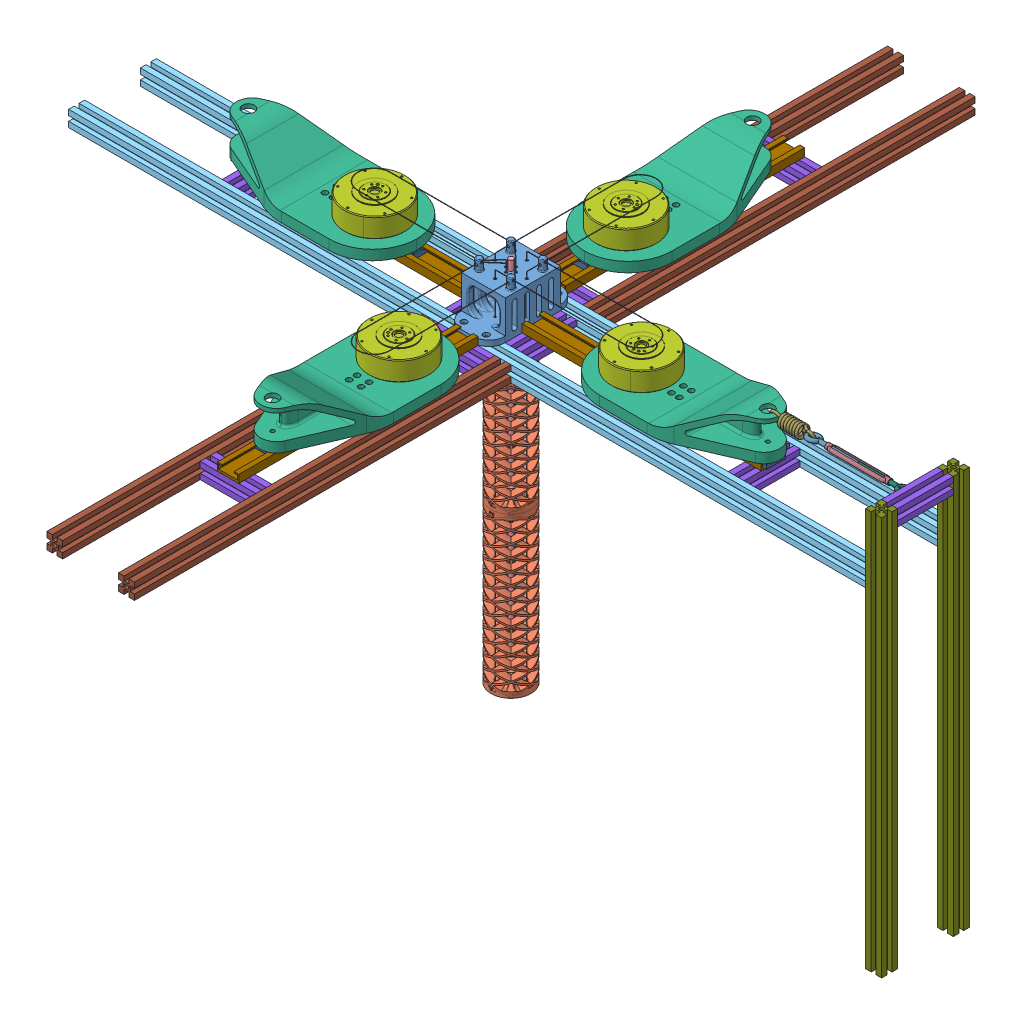
SolidWorks assembly Assemblage, configuration Default. Lengths in mm.
Overall size (1020 500 1055).
53 component instances, 20 part files, 137 mates.
Components (placement in the parent):
- Base-1: Base [Défaut] at (31.9526 22.2291 35.5804) size (55 61.5 110)
- Pièce1-1: Pièce1 [Défaut] at (31.9526 -119.2709 35.5804) x (-1 0 0) z (0 0 1) size (50.03 200 50.02)
- rondelle accroche-1: rondelle accroche [Défaut] at (31.9526 -219.2709 35.5804) size (45.5 4 45.5)
- Pièce1-2: Pièce1 [Défaut] at (31.9526 -319.2709 35.5804) x (-1 0 0) z (0 0 1) size (50.03 200 50.02)
- rondelle accroche-2: rondelle accroche [Défaut] at (31.9526 -419.2709 35.5804) size (45.5 4 45.5)
- Âme-1: Âme [Défaut] at (31.9526 -388.7709 35.5804) size (6 430 6)
- profilé-1: profilé [Défaut] at (-468.0474 -29.2709 80.5804) size (1000 20 20)
- profilé-2: profilé [Défaut] at (-468.0474 -29.2709 -9.4196) size (1000 20 20)
- Support Moteur-1: Support Moteur [Défaut] at (-191.4565 -9.2709 -19.4196) x (0 0 1) z (-1 0 0) size (110 48.5 226.09)
- RMD-X6-V2-1: RMD-X6-V2 [Défaut] at (-460.2739 760.2284 221.0931) x (0 -1 0) z (0.5 0 0.866025) size (38.5 76 76)
- profilé70-1: profilé70 [Défaut] at (-5.5474 -29.2709 70.5804) x (0 0 -1) z (1 0 0) size (70 20 20)
- profilé70-2: profilé70 [Défaut] at (69.4526 -29.2709 70.5804) x (0 0 -1) z (1 0 0) size (70 20 20)
- profilé70-3: profilé70 [Défaut] at (-285.5474 -29.2709 70.5804) x (0 0 -1) z (1 0 0) size (70 20 20)
- Glissiere-5: Glissiere [Défaut] at (4.4526 -19.2709 35.5804) x (0 0 1) z (0 -1 0) size (27 300 10)
- Patin-5: Patin [Défaut] at (-267.5475 -16.2709 23.5804) x (0 0 1) z (-1 0 0) size (24 7 40)
- Patin-6: Patin [Défaut] at (-84.9565 -16.2709 23.5804) x (0 0 1) z (-1 0 0) size (24 7 40)
- profilé472-1: profilé472 [Défaut] at (-13.0474 -29.2709 -19.4196) x (0 0 -1) z (1 0 0) size (472.5 20 20)
- profilé472-2: profilé472 [Défaut] at (76.9526 -29.2709 -19.4196) x (0 0 -1) z (1 0 0) size (472.5 20 20)
- Support Moteur-2: Support Moteur [Défaut] at (86.9526 -9.2709 -161.5842) x (-1 0 0) z (0 0 -1) size (110 48.5 226.09)
- RMD-X6-V2-2: RMD-X6-V2 [Défaut] at (-153.5601 760.2284 -430.4015) x (0 -1 0) z (-0.866025 0 0.5) size (38.5 76 76)
- profilé70-6: profilé70 [Défaut] at (-3.0474 -29.2709 -29.4196) size (70 20 20)
- profilé70-7: profilé70 [Défaut] at (-3.0474 -29.2709 -309.4196) size (70 20 20)
- Glissiere-6: Glissiere [Défaut] at (31.9526 -19.2709 -19.4196) x (-1 0 0) z (0 -1 0) size (27 300 10)
- Patin-7: Patin [Défaut] at (43.9526 -16.2709 -237.6752) x (-1 0 0) z (0 0 -1) size (24 7 40)
- Patin-8: Patin [Défaut] at (43.9526 -16.2709 -55.0842) x (-1 0 0) z (0 0 -1) size (24 7 40)
- Patin-9: Patin [Défaut] at (19.9526 -16.2709 122.1386) size (24 7 40)
- Patin-10: Patin [Défaut] at (19.9526 -16.2709 304.7296) size (24 7 40)
- Glissiere-7: Glissiere [Défaut] at (31.9526 -19.2709 90.5804) x (1 0 0) z (0 -1 0) size (27 300 10)
- profilé70-8: profilé70 [Défaut] at (66.9526 -29.2709 380.5804) x (-1 0 0) z (0 0 -1) size (70 20 20)
- profilé70-9: profilé70 [Défaut] at (66.9526 -29.2709 100.5804) x (-1 0 0) z (0 0 -1) size (70 20 20)
- RMD-X6-V2-3: RMD-X6-V2 [Défaut] at (217.4653 760.2284 497.4559) x (0 -1 0) z (0.866025 0 -0.5) size (38.5 76 76)
- Support Moteur-3: Support Moteur [Défaut] at (-23.0474 -9.2709 228.6386) size (110 48.5 226.09)
- profilé472-3: profilé472 [Défaut] at (-13.0474 -29.2709 90.5804) x (0 0 1) z (-1 0 0) size (472.5 20 20)
- profilé472-4: profilé472 [Défaut] at (76.9526 -29.2709 90.5804) x (0 0 1) z (-1 0 0) size (472.5 20 20)
- Patin-11: Patin [Défaut] at (141.7335 -16.2709 47.5804) x (0 0 -1) z (1 0 0) size (24 7 40)
- Patin-12: Patin [Défaut] at (324.3246 -16.2709 47.5804) x (0 0 -1) z (1 0 0) size (24 7 40)
- Glissiere-8: Glissiere [Défaut] at (59.4526 -19.2709 35.5804) x (0 0 -1) z (0 -1 0) size (27 300 10)
- profilé70-10: profilé70 [Défaut] at (349.4526 -29.2709 0.5804) x (0 0 1) z (-1 0 0) size (70 20 20)
- RMD-X6-V2-4: RMD-X6-V2 [Défaut] at (517.0509 760.2284 -149.9322) x (0 -1 0) z (-0.5 0 -0.866025) size (38.5 76 76)
- Support Moteur-4: Support Moteur [Défaut] at (248.2335 -9.2709 90.5804) x (0 0 -1) z (1 0 0) size (110 48.5 226.09)
- Systeme tension-1: Systeme tension [Default] at (366.6142 -12.8569 63.3429) x (0 0.308944 -0.95108) z (1 0 0) size (18.83 16.19 176.97)
  - Ressort-1: Ressort [Default] at (41.4989 37.8914 -5.9626) size (16.19 16.19 57)
  - Tendeur-1: Tendeur [Default] at (41.4989 37.8914 101.8123) x (0.560693 0.828024 0) z (-0.828024 0.560693 0) size (7 132 18)
    - 4246a05zcmu_01-1: 4246a05zcmu_01 [Default] at origin size (7 79 12)
    - 4246a05zcmu_02-1: 4246a05zcmu_02 [Default] at origin size (5 66 18)
    - 4246a05zcmu_03-1: 4246a05zcmu_03 [Default] at origin size (5 66 18)
- profilé455-1: profilé455 [Défaut] at (541.9526 -453.2709 -9.4196) x (0 1 0) z (0 0 1) size (500 20 20)
- profilé455-2: profilé455 [Défaut] at (541.9526 -453.2709 80.5804) x (0 1 0) z (0 0 1) size (500 20 20)
- profilé70-11: profilé70 [Défaut] at (541.9526 36.7291 0.5804) x (0 0 1) z (-1 0 0) size (70 20 20)
- fil-1: fil [Défaut] at (31.9526 -219.0209 55.5804) size (182.5 258.25 40.5)
- fil2-1: fil2 [Défaut] at (31.9526 -219.0209 35.5804) x (-1 0 0) z (0 0 -1) size (192.5 458.25 40.5)
- fil3-1: fil3 [Défaut] at (51.9526 -221.0209 35.5804) x (0 0 -1) z (1 0 0) size (182.5 258.25 40.5)
- fil4-1: fil4 [Défaut] at (31.9526 -219.0209 35.5804) x (0 0 1) z (-1 0 0) size (192.5 456.25 40.5)
Mates (geometry in assembly coordinates):
- Coïncidente1: coincident anti-aligned: plane of Base-1 through (24.4526 -19.2709 0.5804) normal (0 -1 0); plane of Pièce1-1 through (31.9526 -19.2709 35.5804) normal (0 1 0)
- Coaxiale1: concentric anti-aligned: cylinder of Base-1 through (31.9526 29.2291 35.5804) axis (0 -1 0) radius 3; cylinder of Pièce1-1 through (31.9526 -120.3822 35.5804) axis (0 1 0) radius 3
- Coaxiale2: concentric anti-aligned: cylinder of Base-1 through (25.9526 29.2291 35.5804) axis (0 -1 0) radius 1.25; cylinder of Pièce1-1 through (25.9526 -120.3822 35.5804) axis (0 1 0) radius 1
- Coïncidente2: coincident anti-aligned: plane of Pièce1-1 through (31.9526 -215.2709 35.5804) normal (0 -1 0); plane of rondelle accroche-1 through (31.9526 -215.2709 35.5804) normal (0 1 0)
- Coaxiale3: concentric aligned: cylinder of Pièce1-1 through (31.9526 -215.2709 35.5804) axis (0 -1 0) radius 12.25; cylinder of rondelle accroche-1 through (31.9526 -215.2709 35.5804) axis (0 -1 0) radius 12.5
- Coaxiale4: concentric aligned: cylinder of Pièce1-1 through (51.9526 -118.1596 35.5804) axis (0 -1 0) radius 0.5; cylinder of rondelle accroche-1 through (51.9526 -215.2709 35.5804) axis (0 -1 0) radius 0.5
- Coïncidente3: coincident anti-aligned: plane of Pièce1-1 through (31.9526 -219.2709 35.5804) normal (0 -1 0); plane of Pièce1-2 through (31.9526 -219.2709 35.5804) normal (0 1 0)
- Coaxiale5: concentric anti-aligned: cylinder of Pièce1-1 through (25.9526 -118.1596 35.5804) axis (0 -1 0) radius 1; cylinder of Pièce1-2 through (25.9526 -320.3822 35.5804) axis (0 1 0) radius 1
- Coaxiale6: concentric anti-aligned: cylinder of Pièce1-1 through (25.9526 -118.1596 35.5804) axis (0 -1 0) radius 1; cylinder of Pièce1-2 through (25.9526 -320.3822 35.5804) axis (0 1 0) radius 1
- Coïncidente4: coincident anti-aligned: plane of Pièce1-2 through (31.9526 -415.2709 35.5804) normal (0 -1 0); plane of rondelle accroche-2 through (31.9526 -415.2709 35.5804) normal (0 1 0)
- Coaxiale7: concentric aligned: cylinder of Pièce1-2 through (11.9526 -318.1596 35.5804) axis (0 -1 0) radius 0.5; cylinder of rondelle accroche-2 through (11.9526 -415.2709 35.5804) axis (0 -1 0) radius 0.5
- Coaxiale8: concentric aligned: cylinder of Pièce1-2 through (31.9526 -415.2709 35.5804) axis (0 -1 0) radius 12.25; cylinder of rondelle accroche-2 through (31.9526 -415.2709 35.5804) axis (0 -1 0) radius 12.5
- Coïncidente5: coincident: plane of Base-1 through (31.9526 41.2291 35.5804) normal (0 1 0); plane of Âme-1 through (31.9526 41.2291 35.5804) normal (0 1 0)
- Coaxiale9: concentric aligned: cylinder of Base-1 through (31.9526 29.2291 35.5804) axis (0 -1 0) radius 3; cylinder of Âme-1 through (31.9526 41.2291 35.5804) axis (0 -1 0) radius 3
- Coïncidente9: coincident anti-aligned: plane of Base-1 through (24.4526 -19.2709 0.5804) normal (0 -1 0); plane of profilé-1 through (531.9526 -19.2709 90.5804) normal (0 1 0)
- Coïncidente10: coincident aligned: plane of Base-1 through (24.4526 -19.2709 90.5804) normal (0 0 1); plane of profilé-1 through (531.9526 -26.2709 90.5804) normal (0 0 1)
- Coïncidente11: coincident anti-aligned: plane of Base-1 through (24.4526 -19.2709 0.5804) normal (0 -1 0); plane of profilé-2 through (531.9526 -19.2709 0.5804) normal (0 1 0)
- Coïncidente12: coincident aligned: plane of Base-1 through (24.4526 -19.2709 -19.4196) normal (0 0 -1); plane of profilé-2 through (531.9526 -19.2709 -19.4196) normal (0 0 -1)
- Coïncidente13: coincident aligned: plane of profilé-1 through (531.9526 -29.2709 80.5804) normal (1 0 0); plane of profilé-2 through (531.9526 -29.2709 -9.4196) normal (1 0 0)
- Distance1: distance = 472.5 mm aligned: plane of Base-1 through (59.4526 29.2291 90.5804) normal (1 0 0); plane of profilé-1 through (531.9526 -29.2709 80.5804) normal (1 0 0)
- Coïncidente41: coincident anti-aligned: plane of Support Moteur-1 through (-191.4565 3.2291 -19.4196) normal (0 1 0); plane of RMD-X6-V2-1 through (-113.4088 3.2291 20.8304) normal (0 -1 0)
- Coaxiale15: concentric anti-aligned: cylinder of Support Moteur-1 through (-138.9565 -9.2709 35.5804) axis (0 1 0) radius 30; cylinder of RMD-X6-V2-1 through (-138.9565 -2.5209 35.5804) axis (0 -1 0) radius 29.5
- Coaxiale16: concentric aligned: cylinder of Support Moteur-1 through (-109.5116 -9.2709 18.5804) axis (0 1 0) radius 1.75; cylinder of RMD-X6-V2-1 through (-109.5116 3.2291 18.5804) axis (0 1 0) radius 1.25
- Coïncidente42: coincident anti-aligned: plane of profilé-2 through (531.9526 -26.2709 0.5804) normal (0 0 1); plane of profilé70-1 through (-5.5474 -29.2709 0.5804) normal (0 0 -1)
- Coïncidente43: coincident aligned: plane of profilé-2 through (531.9526 -19.2709 0.5804) normal (0 1 0); plane of profilé70-1 through (4.4526 -19.2709 0.5804) normal (0 1 0)
- Coïncidente44: coincident anti-aligned: plane of Base-1 through (4.4526 29.2291 90.5804) normal (-1 0 0); plane of profilé70-1 through (4.4526 -26.2709 0.5804) normal (1 0 0)
- Coïncidente45: coincident anti-aligned: plane of profilé-2 through (531.9526 -26.2709 0.5804) normal (0 0 1); plane of profilé70-2 through (69.4526 -29.2709 0.5804) normal (0 0 -1)
- Coïncidente46: coincident aligned: plane of profilé-2 through (531.9526 -19.2709 0.5804) normal (0 1 0); plane of profilé70-2 through (79.4526 -19.2709 0.5804) normal (0 1 0)
- Coïncidente47: coincident anti-aligned: plane of Base-1 through (59.4526 29.2291 90.5804) normal (1 0 0); plane of profilé70-2 through (59.4526 -19.2709 0.5804) normal (-1 0 0)
- Coïncidente48: coincident anti-aligned: plane of profilé-2 through (531.9526 -26.2709 0.5804) normal (0 0 1); plane of profilé70-3 through (-285.5474 -29.2709 0.5804) normal (0 0 -1)
- Coïncidente49: coincident aligned: plane of profilé-2 through (531.9526 -19.2709 0.5804) normal (0 1 0); plane of profilé70-3 through (-275.5474 -19.2709 0.5804) normal (0 1 0)
- Coïncidente51: coincident anti-aligned: plane of profilé70-3 through (-288.5474 -19.2709 0.5804) normal (0 1 0); plane of Glissiere-5 through (-295.5474 -19.2709 22.0804) normal (0 -1 0)
- Coïncidente52: coincident aligned: plane of profilé70-3 through (-295.5474 -19.2709 0.5804) normal (-1 0 0); plane of Glissiere-5 through (-295.5474 -19.2709 35.5804) normal (-1 0 0)
- Distance3: distance = 21.5 mm anti-aligned: plane of Glissiere-5 through (-295.5474 -19.2709 22.0804) normal (0 0 -1); plane of profilé-2 through (531.9526 -26.2709 0.5804) normal (0 0 1)
- Coïncidente55: coincident anti-aligned: plane of Glissiere-5 through (-295.5474 -16.2709 47.5804) normal (0 1 0); plane of Patin-5 through (-307.5475 -16.2709 23.5804) normal (0 -1 0)
- Coïncidente56: coincident anti-aligned: plane of Glissiere-5 through (-295.5474 -10.7709 23.5804) normal (0 0 1); plane of Patin-5 through (-307.5475 -16.2709 23.5804) normal (0 0 -1)
- Coïncidente57: coincident anti-aligned: plane of Glissiere-5 through (-295.5474 -16.2709 47.5804) normal (0 1 0); plane of Patin-6 through (-124.9565 -16.2709 23.5804) normal (0 -1 0)
- Coïncidente58: coincident anti-aligned: plane of Glissiere-5 through (-295.5474 -10.7709 23.5804) normal (0 0 1); plane of Patin-6 through (-124.9565 -16.2709 23.5804) normal (0 0 -1)
- Coïncidente59: coincident anti-aligned: plane of Support Moteur-1 through (-191.4565 -9.2709 -19.4196) normal (0 -1 0); plane of Glissiere-5 through (-295.5474 -9.2709 22.0804) normal (0 1 0)
- Coaxiale18: concentric anti-aligned: cylinder of Support Moteur-1 through (-297.5475 3.2291 35.5804) axis (0 -1 0) radius 2.5; cylinder of Patin-5 through (-297.5475 -16.2709 35.5804) axis (0 1 0) radius 2.5
- Coïncidente60: coincident aligned: plane of profilé70-3 through (-295.5474 -19.2709 0.5804) normal (-1 0 0); plane of Glissiere-5 through (-295.5474 -19.2709 35.5804) normal (-1 0 0)
- Coïncidente61: coincident aligned: plane of profilé70-3 through (-295.5474 -19.2709 0.5804) normal (-1 0 0); plane of Glissiere-5 through (-295.5474 -19.2709 35.5804) normal (-1 0 0)
- Coïncidente63: coincident aligned: plane of profilé70-1 through (4.4526 -26.2709 0.5804) normal (1 0 0); plane of Glissiere-5 through (4.4526 -19.2709 35.5804) normal (1 0 0)
- Coïncidente64: coincident anti-aligned: plane of profilé-2 through (531.9526 -19.2709 -19.4196) normal (0 0 -1); plane of profilé472-1 through (-13.0474 -29.2709 -19.4196) normal (0 0 1)
- Coïncidente65: coincident aligned: plane of profilé-2 through (531.9526 -19.2709 -12.4196) normal (0 1 0); plane of profilé472-1 through (-16.0474 -19.2709 -491.9196) normal (0 1 0)
- Coïncidente66: coincident anti-aligned: plane of profilé-2 through (531.9526 -19.2709 -19.4196) normal (0 0 -1); plane of profilé472-2 through (76.9526 -29.2709 -19.4196) normal (0 0 1)
- Coïncidente67: coincident aligned: plane of profilé-2 through (531.9526 -19.2709 -12.4196) normal (0 1 0); plane of profilé472-2 through (73.9526 -19.2709 -491.9196) normal (0 1 0)
- Coïncidente73: coincident anti-aligned: plane of profilé70-7 through (66.9526 -19.2709 -312.4196) normal (0 1 0); plane of Glissiere-6 through (45.4526 -19.2709 -319.4196) normal (0 -1 0)
- Coïncidente74: coincident aligned: plane of profilé70-7 through (66.9526 -19.2709 -319.4196) normal (0 0 -1); plane of Glissiere-6 through (31.9526 -19.2709 -319.4196) normal (0 0 -1)
- Coïncidente75: coincident anti-aligned: plane of Glissiere-6 through (19.9526 -16.2709 -319.4196) normal (0 1 0); plane of Patin-8 through (43.9526 -16.2709 -95.0842) normal (0 -1 0)
- Coïncidente76: coincident anti-aligned: plane of Glissiere-6 through (43.9526 -10.7709 -319.4196) normal (-1 0 0); plane of Patin-8 through (43.9526 -16.2709 -95.0842) normal (1 0 0)
- Coïncidente77: coincident aligned: plane of profilé70-7 through (66.9526 -19.2709 -319.4196) normal (0 0 -1); plane of Glissiere-6 through (31.9526 -19.2709 -319.4196) normal (0 0 -1)
- Coïncidente78: coincident aligned: plane of profilé70-7 through (66.9526 -19.2709 -319.4196) normal (0 0 -1); plane of Glissiere-6 through (31.9526 -19.2709 -319.4196) normal (0 0 -1)
- Coïncidente79: coincident anti-aligned: plane of Glissiere-6 through (19.9526 -16.2709 -319.4196) normal (0 1 0); plane of Patin-7 through (43.9526 -16.2709 -277.6752) normal (0 -1 0)
- Coaxiale20: concentric anti-aligned: cylinder of Support Moteur-2 through (31.9526 3.2291 -267.6752) axis (0 -1 0) radius 2.5; cylinder of Patin-7 through (31.9526 -16.2709 -267.6752) axis (0 1 0) radius 2.5
- Coïncidente80: coincident aligned: plane of profilé70-6 through (66.9526 -26.2709 -19.4196) normal (0 0 1); plane of Glissiere-6 through (31.9526 -19.2709 -19.4196) normal (0 0 1)
- Coïncidente81: coincident anti-aligned: plane of Support Moteur-2 through (86.9526 -9.2709 -161.5842) normal (0 -1 0); plane of Glissiere-6 through (45.4526 -9.2709 -319.4196) normal (0 1 0)
- Coïncidente82: coincident anti-aligned: plane of Glissiere-6 through (43.9526 -10.7709 -319.4196) normal (-1 0 0); plane of Patin-7 through (43.9526 -16.2709 -277.6752) normal (1 0 0)
- Coïncidente83: coincident anti-aligned: plane of Support Moteur-2 through (86.9526 3.2291 -161.5842) normal (0 1 0); plane of RMD-X6-V2-2 through (46.7026 3.2291 -83.5365) normal (0 -1 0)
- Coaxiale21: concentric aligned: cylinder of Support Moteur-2 through (48.9526 -9.2709 -79.6393) axis (0 1 0) radius 1.75; cylinder of RMD-X6-V2-2 through (48.9526 3.2291 -79.6393) axis (0 1 0) radius 1.25
- Coaxiale22: concentric anti-aligned: cylinder of Support Moteur-2 through (31.9526 -9.2709 -109.0842) axis (0 1 0) radius 30; cylinder of RMD-X6-V2-2 through (31.9526 -2.5209 -109.0842) axis (0 -1 0) radius 29.5
- Coïncidente85: coincident anti-aligned: plane of profilé472-1 through (-3.0474 -39.2709 -491.9196) normal (1 0 0); plane of profilé70-7 through (-3.0474 -29.2709 -309.4196) normal (-1 0 0)
- Coïncidente86: coincident aligned: plane of profilé472-1 through (-16.0474 -19.2709 -491.9196) normal (0 1 0); plane of profilé70-7 through (66.9526 -19.2709 -299.4196) normal (0 1 0)
- Coïncidente87: coincident anti-aligned: plane of profilé472-2 through (66.9526 -19.2709 -491.9196) normal (-1 0 0); plane of profilé70-7 through (66.9526 -29.2709 -309.4196) normal (1 0 0)
- Coïncidente88: coincident anti-aligned: plane of profilé472-1 through (-3.0474 -39.2709 -491.9196) normal (1 0 0); plane of profilé70-6 through (-3.0474 -29.2709 -29.4196) normal (-1 0 0)
- Coïncidente89: coincident aligned: plane of profilé472-1 through (-3.0474 -19.2709 -491.9196) normal (0 1 0); plane of profilé70-6 through (66.9526 -19.2709 -19.4196) normal (0 1 0)
- Coïncidente90: coincident anti-aligned: plane of profilé-2 through (531.9526 -19.2709 -19.4196) normal (0 0 -1); plane of profilé70-6 through (66.9526 -26.2709 -19.4196) normal (0 0 1)
- Distance4: distance = 7.5 mm anti-aligned: plane of profilé472-1 through (-3.0474 -26.2709 -491.9196) normal (1 0 0); plane of Base-1 through (4.4526 29.2291 90.5804) normal (-1 0 0)
- Distance6: distance = 21.5 mm anti-aligned: plane of Glissiere-6 through (18.4526 -19.2709 -319.4196) normal (-1 0 0); plane of profilé472-1 through (-3.0474 -26.2709 -491.9196) normal (1 0 0)
- Coïncidente94: coincident aligned: plane of profilé70-8 through (-3.0474 -19.2709 370.5804) normal (0 1 0); plane of profilé472-4 through (79.9526 -19.2709 563.0804) normal (0 1 0)
- Coïncidente95: coincident anti-aligned: plane of Glissiere-7 through (18.4526 -19.2709 390.5804) normal (0 -1 0); plane of profilé70-8 through (-3.0474 -19.2709 383.5804) normal (0 1 0)
- Coïncidente96: coincident anti-aligned: plane of Patin-9 through (19.9526 -16.2709 162.1386) normal (-1 0 0); plane of Glissiere-7 through (19.9526 -10.7709 390.5804) normal (1 0 0)
- Coïncidente97: coincident aligned: plane of Glissiere-7 through (31.9526 -19.2709 390.5804) normal (0 0 1); plane of profilé70-8 through (-3.0474 -19.2709 390.5804) normal (0 0 1)
- Coïncidente98: coincident anti-aligned: plane of Glissiere-7 through (18.4526 -9.2709 390.5804) normal (0 1 0); plane of Support Moteur-3 through (-23.0474 -9.2709 228.6386) normal (0 -1 0)
- Coïncidente99: coincident anti-aligned: plane of Patin-9 through (19.9526 -16.2709 162.1386) normal (0 -1 0); plane of Glissiere-7 through (43.9526 -16.2709 390.5804) normal (0 1 0)
- Coïncidente100: coincident anti-aligned: plane of Patin-10 through (19.9526 -16.2709 344.7296) normal (0 -1 0); plane of Glissiere-7 through (43.9526 -16.2709 390.5804) normal (0 1 0)
- Coïncidente101: coincident aligned: plane of Glissiere-7 through (31.9526 -19.2709 90.5804) normal (0 0 -1); plane of profilé70-9 through (-3.0474 -26.2709 90.5804) normal (0 0 -1)
- Coïncidente102: coincident aligned: plane of Glissiere-7 through (31.9526 -19.2709 390.5804) normal (0 0 1); plane of profilé70-8 through (-3.0474 -19.2709 390.5804) normal (0 0 1)
- Coïncidente103: coincident anti-aligned: plane of RMD-X6-V2-3 through (17.2026 3.2291 150.5908) normal (0 -1 0); plane of Support Moteur-3 through (-23.0474 3.2291 228.6386) normal (0 1 0)
- Coïncidente104: coincident aligned: plane of Glissiere-7 through (31.9526 -19.2709 390.5804) normal (0 0 1); plane of profilé70-8 through (-3.0474 -19.2709 390.5804) normal (0 0 1)
- Coïncidente105: coincident anti-aligned: plane of Patin-10 through (19.9526 -16.2709 344.7296) normal (-1 0 0); plane of Glissiere-7 through (19.9526 -10.7709 390.5804) normal (1 0 0)
- Coaxiale24: concentric anti-aligned: cylinder of RMD-X6-V2-3 through (31.9526 -2.5209 176.1386) axis (0 -1 0) radius 29.5; cylinder of Support Moteur-3 through (31.9526 -9.2709 176.1386) axis (0 1 0) radius 30
- Coaxiale25: concentric aligned: cylinder of RMD-X6-V2-3 through (14.9526 3.2291 146.6937) axis (0 1 0) radius 1.25; cylinder of Support Moteur-3 through (14.9526 -9.2709 146.6937) axis (0 1 0) radius 1.75
- Coaxiale26: concentric anti-aligned: cylinder of Patin-10 through (31.9526 -16.2709 334.7296) axis (0 1 0) radius 2.5; cylinder of Support Moteur-3 through (31.9526 3.2291 334.7296) axis (0 -1 0) radius 2.5
- Coïncidente106: coincident anti-aligned: plane of profilé70-9 through (66.9526 -29.2709 100.5804) normal (1 0 0); plane of profilé472-4 through (66.9526 -39.2709 563.0804) normal (-1 0 0)
- Coïncidente107: coincident aligned: plane of profilé70-9 through (-3.0474 -19.2709 90.5804) normal (0 1 0); plane of profilé472-4 through (66.9526 -19.2709 563.0804) normal (0 1 0)
- Coïncidente108: coincident anti-aligned: plane of profilé70-8 through (-3.0474 -29.2709 380.5804) normal (-1 0 0); plane of profilé472-3 through (-3.0474 -19.2709 563.0804) normal (1 0 0)
- Coïncidente109: coincident anti-aligned: plane of profilé70-8 through (66.9526 -29.2709 380.5804) normal (1 0 0); plane of profilé472-4 through (66.9526 -39.2709 563.0804) normal (-1 0 0)
- Distance7: distance = 21.5 mm anti-aligned: plane of Glissiere-7 through (45.4526 -19.2709 390.5804) normal (1 0 0); plane of profilé472-4 through (66.9526 -26.2709 563.0804) normal (-1 0 0)
- Coïncidente111: coincident anti-aligned: plane of profilé70-9 through (-3.0474 -29.2709 100.5804) normal (-1 0 0); plane of profilé472-3 through (-3.0474 -19.2709 563.0804) normal (1 0 0)
- Coïncidente112: coincident aligned: plane of profilé472-3 through (-10.0474 -19.2709 563.0804) normal (0 1 0); plane of profilé472-4 through (79.9526 -19.2709 563.0804) normal (0 1 0)
- Coïncidente113: coincident aligned: plane of profilé-1 through (531.9526 -19.2709 90.5804) normal (0 1 0); plane of profilé472-4 through (66.9526 -19.2709 563.0804) normal (0 1 0)
- Coïncidente114: coincident aligned: plane of profilé70-9 through (-3.0474 -26.2709 90.5804) normal (0 0 -1); plane of profilé472-4 through (76.9526 -29.2709 90.5804) normal (0 0 -1)
- Coïncidente116: coincident aligned: plane of profilé70-9 through (-3.0474 -26.2709 90.5804) normal (0 0 -1); plane of profilé472-3 through (-13.0474 -29.2709 90.5804) normal (0 0 -1)
- Coïncidente117: coincident anti-aligned: plane of profilé-1 through (531.9526 -26.2709 90.5804) normal (0 0 1); plane of profilé472-4 through (76.9526 -29.2709 90.5804) normal (0 0 -1)
- Coïncidente118: coincident aligned: plane of profilé472-2 through (86.9526 -26.2709 -491.9196) normal (1 0 0); plane of profilé472-4 through (86.9526 -19.2709 563.0804) normal (1 0 0)
- Coïncidente119: coincident anti-aligned: plane of RMD-X6-V2-4 through (170.1858 3.2291 50.3304) normal (0 -1 0); plane of Support Moteur-4 through (248.2335 3.2291 90.5804) normal (0 1 0)
- Coïncidente120: coincident anti-aligned: plane of Glissiere-8 through (359.4526 -19.2709 49.0804) normal (0 -1 0); plane of profilé70-10 through (352.4526 -19.2709 70.5804) normal (0 1 0)
- Coïncidente121: coincident aligned: plane of Glissiere-8 through (359.4526 -19.2709 35.5804) normal (1 0 0); plane of profilé70-10 through (359.4526 -19.2709 70.5804) normal (1 0 0)
- Coïncidente122: coincident aligned: plane of Glissiere-8 through (359.4526 -19.2709 35.5804) normal (1 0 0); plane of profilé70-10 through (359.4526 -19.2709 70.5804) normal (1 0 0)
- Coïncidente123: coincident anti-aligned: plane of Patin-11 through (181.7335 -16.2709 47.5804) normal (0 -1 0); plane of Glissiere-8 through (359.4526 -16.2709 23.5804) normal (0 1 0)
- Coïncidente124: coincident anti-aligned: plane of Glissiere-8 through (359.4526 -9.2709 49.0804) normal (0 1 0); plane of Support Moteur-4 through (248.2335 -9.2709 90.5804) normal (0 -1 0)
- Coïncidente125: coincident anti-aligned: plane of Patin-12 through (364.3246 -16.2709 47.5804) normal (0 0 1); plane of Glissiere-8 through (359.4526 -10.7709 47.5804) normal (0 0 -1)
- Coïncidente126: coincident anti-aligned: plane of Patin-12 through (364.3246 -16.2709 47.5804) normal (0 -1 0); plane of Glissiere-8 through (359.4526 -16.2709 23.5804) normal (0 1 0)
- Coïncidente127: coincident aligned: plane of Glissiere-8 through (359.4526 -19.2709 35.5804) normal (1 0 0); plane of profilé70-10 through (359.4526 -19.2709 70.5804) normal (1 0 0)
- Coïncidente128: coincident anti-aligned: plane of Patin-11 through (181.7335 -16.2709 47.5804) normal (0 0 1); plane of Glissiere-8 through (359.4526 -10.7709 47.5804) normal (0 0 -1)
- Coaxiale27: concentric aligned: cylinder of RMD-X6-V2-4 through (166.2887 3.2291 52.5804) axis (0 1 0) radius 1.25; cylinder of Support Moteur-4 through (166.2887 -9.2709 52.5804) axis (0 1 0) radius 1.75
- Coaxiale28: concentric anti-aligned: cylinder of Patin-12 through (354.3246 -16.2709 35.5804) axis (0 1 0) radius 2.5; cylinder of Support Moteur-4 through (354.3246 3.2291 35.5804) axis (0 -1 0) radius 2.5
- Coaxiale30: concentric anti-aligned: cylinder of RMD-X6-V2-4 through (195.7335 -2.5209 35.5804) axis (0 -1 0) radius 29.5; cylinder of Support Moteur-4 through (195.7335 -9.2709 35.5804) axis (0 1 0) radius 30
- Coïncidente129: coincident aligned: plane of Glissiere-8 through (359.4526 -19.2709 35.5804) normal (1 0 0); plane of profilé70-10 through (359.4526 -19.2709 70.5804) normal (1 0 0)
- Coïncidente130: coincident aligned: plane of profilé70-2 through (59.4526 -19.2709 0.5804) normal (-1 0 0); plane of Glissiere-8 through (59.4526 -19.2709 35.5804) normal (-1 0 0)
- Coïncidente131: coincident anti-aligned: plane of profilé70-2 through (79.4526 -19.2709 0.5804) normal (0 1 0); plane of Glissiere-8 through (359.4526 -19.2709 49.0804) normal (0 -1 0)
- Coïncidente132: coincident anti-aligned: plane of profilé-1 through (531.9526 -19.2709 70.5804) normal (0 0 -1); plane of profilé70-10 through (349.4526 -29.2709 70.5804) normal (0 0 1)
- Distance8: distance = 21.5 mm anti-aligned: plane of Glissiere-8 through (359.4526 -19.2709 49.0804) normal (0 0 1); plane of profilé-1 through (531.9526 -19.2709 70.5804) normal (0 0 -1)
- Parallèle1: parallel anti-aligned: line of profilé-1 through (531.9526 -19.2709 70.5804) axis (-1 0 0); cylinder of Systeme tension-1/Tendeur-1/4246a05zcmu_02-1 through (443.1765 36.0017 35.5804) axis (1 0 0) radius 2.5
- Coïncidente134: coincident anti-aligned: plane of profilé-2 through (531.9526 -29.2709 -9.4196) normal (1 0 0); plane of profilé455-1 through (531.9526 46.7291 0.5804) normal (-1 0 0)
- Coïncidente135: coincident aligned: plane of profilé-2 through (531.9526 -19.2709 -19.4196) normal (0 0 -1); plane of profilé455-1 through (531.9526 46.7291 -19.4196) normal (0 0 -1)
- Distance9: distance = 66 mm aligned: plane of profilé455-1 through (541.9526 46.7291 -9.4196) normal (0 1 0); plane of profilé-2 through (531.9526 -19.2709 0.5804) normal (0 1 0)
- Coïncidente137: coincident anti-aligned: plane of profilé-1 through (531.9526 -29.2709 80.5804) normal (1 0 0); plane of profilé455-2 through (531.9526 46.7291 90.5804) normal (-1 0 0)
- Coïncidente138: coincident aligned: plane of profilé-1 through (531.9526 -26.2709 90.5804) normal (0 0 1); plane of profilé455-2 through (538.9526 46.7291 90.5804) normal (0 0 1)
- Coïncidente140: coincident anti-aligned: plane of profilé455-1 through (551.9526 46.7291 0.5804) normal (0 0 1); plane of profilé70-11 through (541.9526 36.7291 0.5804) normal (0 0 -1)
- Coïncidente141: coincident aligned: plane of profilé455-1 through (551.9526 46.7291 -6.4196) normal (1 0 0); plane of profilé70-11 through (551.9526 46.7291 70.5804) normal (1 0 0)
- Coïncidente142: coincident aligned: plane of profilé455-1 through (541.9526 46.7291 -9.4196) normal (0 1 0); plane of profilé70-11 through (544.9526 46.7291 70.5804) normal (0 1 0)
- Coïncidente143: coincident aligned: plane of profilé455-2 through (541.9526 46.7291 80.5804) normal (0 1 0); plane of profilé70-11 through (544.9526 46.7291 70.5804) normal (0 1 0)
- Distance12: distance = 35 mm: cylinder of Systeme tension-1/Tendeur-1/4246a05zcmu_03-1 through (493.6765 36.0017 35.5804) axis (-1 0 0) radius 2.5; plane of profilé455-2 through (531.9526 46.7291 70.5804) normal (0 0 -1)
- Coaxiale31: concentric anti-aligned: cylinder of Base-1 through (31.9526 29.2291 55.5804) axis (0 -1 0) radius 1.25; cylinder of fil-1 through (31.9526 -219.0209 55.5804) axis (0 1 0) radius 0.25
- Coaxiale32: concentric aligned: cylinder of Base-1 through (31.9526 29.2291 15.5804) axis (0 -1 0) radius 1.25; cylinder of fil-1 through (31.9526 37.9791 15.5804) axis (0 -1 0) radius 0.25
- Coaxiale36: concentric anti-aligned: cylinder of Base-1 through (31.9526 29.2291 29.5804) axis (0 -1 0) radius 1.25; cylinder of fil2-1 through (31.9526 -160.3102 29.5804) axis (0 1 0) radius 0.25
- Coaxiale37: concentric aligned: cylinder of Base-1 through (31.9526 29.2291 41.5804) axis (0 -1 0) radius 1.25; cylinder of fil2-1 through (31.9526 37.9791 41.5804) axis (0 -1 0) radius 0.25
- Tangent7: tangent: plane of Base-1 through (31.9526 38.7291 41.5804) normal (0 1 0); cylinder of fil2-1 through (16.2354 38.9791 55.333) axis (0.752577 0 -0.658505) radius 0.25
- Coaxiale38: concentric anti-aligned: cylinder of Base-1 through (51.9526 29.2291 35.5804) axis (0 -1 0) radius 1.25; cylinder of fil3-1 through (51.9526 -221.0209 35.5804) axis (0 1 0) radius 0.25
- Coaxiale39: concentric aligned: cylinder of Base-1 through (11.9526 29.2291 35.5804) axis (0 -1 0) radius 1.25; cylinder of fil3-1 through (11.9526 35.9791 35.5804) axis (0 -1 0) radius 0.25
- Tangent8: tangent: plane of Base-1 through (11.9526 36.7291 35.5804) normal (0 1 0); cylinder of fil3-1 through (11.9526 36.9791 -126.4196) axis (0 0 1) radius 0.25
- Coaxiale40: concentric anti-aligned: cylinder of Base-1 through (25.9526 29.2291 35.5804) axis (0 -1 0) radius 1.25; cylinder of fil4-1 through (25.9526 -162.2562 35.5804) axis (0 1 0) radius 0.25
- Coaxiale41: concentric aligned: cylinder of Base-1 through (37.9526 29.2291 35.5804) axis (0 -1 0) radius 1.25; cylinder of fil4-1 through (37.9526 35.9791 35.5804) axis (0 -1 0) radius 0.25
- Tangent9: tangent: plane of Base-1 through (25.9526 36.7291 35.5804) normal (0 1 0); cylinder of fil4-1 through (25.2941 36.9791 36.333) axis (-0.658505 0 0.752577) radius 0.25
- Tangent12: tangent: plane of Base-1 through (31.9526 38.7291 15.5804) normal (0 1 0); cylinder of fil-1 through (193.9526 38.9791 15.5804) axis (-1 0 0) radius 0.25
